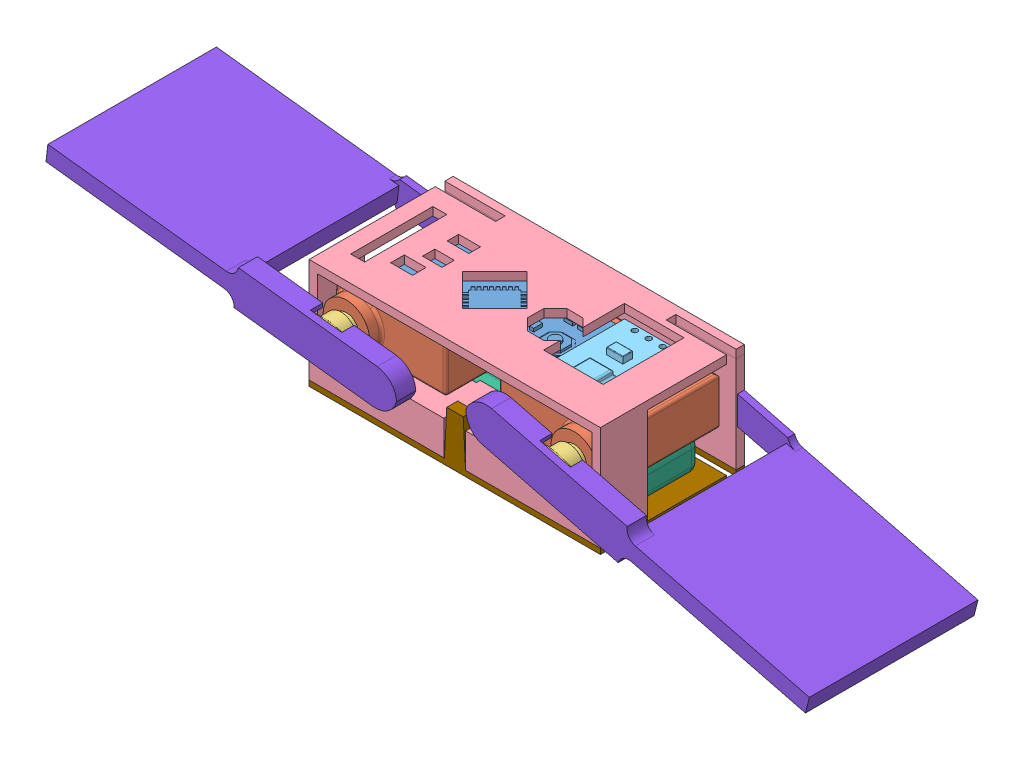
SolidWorks assembly Smarticle- Assembly, configuration Default. Lengths in mm.
Overall size (371.46 24.49 192.23).
15 component instances, 9 part files, 21 mates.
Components (placement in the parent):
- Arduino Pro Mini-1: Arduino Pro Mini [Varsayılan] at (11.3668 -0.6942 -27.9476) size (331.39 1.8 192.23)
- Servo - Assembly-1: Servo - Assembly [Default] at (118.8574 26.3366 -44.2097) x (1 0 0) z (0 -1 0) size (29.74 26.5 12.2) (flexible)
  - Servo - Body-1: Servo - Body [Default] at (-78.8577 -3.7379 27.0308) size (20.3 22.2 8.7)
  - Servo - Horn-1: Servo - Horn [Default] at (-62.9077 22.0121 31.2808) x (0.969467 0 0.245222) z (-0.245222 0 0.969467) size (27 6.5 5.75)
- Servo - Assembly-2: Servo - Assembly [Default] at (-48.4909 -36.2251 -44.2097) x (-1 0 0) z (0 1 0) size (29.69 26.5 8.83) (flexible)
  - Servo - Body-1: Servo - Body [Default] at (-78.8577 -3.7379 27.0308) size (20.3 22.2 8.7)
  - Servo - Horn-1: Servo - Horn [Default] at (-62.9077 22.0121 31.2808) x (0.993313 0 0.115453) z (-0.115453 0 0.993313) size (27 6.5 5.75)
- Case-1: Case [Default] at (8.6669 3.3558 -50.9476) x (1 0 0) z (0 -1 0) size (53.12 26.25 19.05)
- Microphone-1: Microphone [Default] at (56.3851 -0.6942 307.9213) x (0 0 1) z (-1 0 0) size (14.75 2.8 10.85)
- Battery - Assembly-1: Battery - Assembly [Default] at (3.7311 4.5627 -34.4908) x (-1 0 0) z (0 -1 0) size (45.75 12.5 7.58)
  - Battery - Body-1: Battery - Body [Default] at (-55.7734 -0.4976 13.7569) size (35.5 11.1 5.75)
  - Battery - Connector-1: Battery - Connector [Default] at (-20.2734 -1.1976 13.9319) size (10.25 12.5 7.4)
- Servo - Solar Arm-1: Servo - Solar Arm [Default] at (56.8763 -1.6973 -20.1976) x (0.969467 -0.245222 0) z (0 0 -1) size (64.2 6.75 32.5)
- Servo - Solar Arm-2: Servo - Solar Arm [Default] at (14.1286 -8.3085 -20.1976) x (-0.993313 0.115453 0) z (0 0 -1) size (64.2 6.75 32.5)
- Battery Back-1: Battery Back [Default] at (-152.2376 -16.6942 -37.1314) size (53.12 9.25 26.25)
Mates (geometry in assembly coordinates):
- Coincident5: coincident aligned: plane of Servo - Assembly-1/Servo - Body-1 through (39.9997 -0.6942 -47.9476) normal (0 1 0); plane of Servo - Assembly-2/Servo - Body-1 through (30.3669 -0.6942 -47.9476) normal (0 1 0)
- Coincident6: coincident aligned: plane of Servo - Assembly-1/Servo - Body-1 through (39.9997 -9.1942 -27.9476) normal (0 0 1); plane of Servo - Assembly-2/Servo - Body-1 through (30.3669 -0.6942 -27.9476) normal (0 0 1)
- Coincident8: coincident anti-aligned: plane of Servo - Assembly-2/Servo - Body-1 through (30.3669 -0.6942 -47.9476) normal (0 1 0); plane of Arduino Pro Mini-1 through (11.3668 -0.6942 -27.9476) normal (0 -1 0)
- Coincident15: coincident aligned: plane of Arduino Pro Mini-1 through (11.3668 0.1058 -27.9476) normal (0 0 1); plane of Servo - Assembly-2/Servo - Body-1 through (30.3669 -0.6942 -27.9476) normal (0 0 1)
- Coincident19: coincident anti-aligned: plane of Arduino Pro Mini-1 through (44.3668 0.1058 -27.9476) normal (1 0 0); plane of Microphone-1 through (44.3668 0.9058 -46.5116) normal (-1 0 0)
- Coincident20: coincident anti-aligned: plane of Servo - Assembly-1/Servo - Body-1 through (39.9997 -0.6942 -47.9476) normal (0 1 0); plane of Microphone-1 through (56.3851 -0.6942 307.9213) normal (0 -1 0)
- Parallel1: parallel anti-aligned: plane of Case-1 through (8.6669 -68.8322 -49.4476) normal (0 0 1); plane of Battery - Assembly-1/Battery - Connector-1 through (24.0046 -16.7692 -45.7932) normal (0 0 -1)
- Coincident23: coincident anti-aligned: plane of Servo - Assembly-2/Servo - Body-1 through (10.1669 -0.6942 -47.9476) normal (-1 0 0); plane of Case-1 through (10.1669 -25.1697 -24.6976) normal (1 0 0)
- Coincident24: coincident aligned: plane of Servo - Assembly-1/Servo - Body-1 through (55.2168 -9.1942 -47.9476) normal (1 0 0); plane of Microphone-1 through (55.2168 0.9058 -47.2399) normal (1 0 0)
- Coincident27: coincident anti-aligned: plane of Servo - Assembly-1/Servo - Horn-1 through (55.9497 -4.9442 -21.4476) normal (0 0 1); plane of Servo - Solar Arm-1 through (56.8763 -1.6973 -21.4476) normal (0 0 -1)
- Distance1: distance = 1.5 mm anti-aligned: plane of Servo - Assembly-1/Servo - Body-1 through (39.9997 -9.1942 -47.9476) normal (0 0 -1); plane of Case-1 through (8.6669 -68.8322 -49.4476) normal (0 0 1)
- Coincident29: coincident anti-aligned: plane of Servo - Assembly-2/Servo - Horn-1 through (14.4169 -4.9442 -21.4476) normal (0 0 1); plane of Servo - Solar Arm-2 through (14.1286 -8.3085 -21.4476) normal (0 0 -1)
- Width3: width aligned: plane of Servo - Solar Arm-2 through (14.225 -2.0906 -23.6976) normal (-0.015496 -0.99988 0); plane of Servo - Solar Arm-2 through (14.2352 -7.8225 -23.6976) normal (0.214253 0.976778 0); plane of Servo - Assembly-2/Servo - Horn-1 through (13.7983 -7.7365 -21.4476) normal (-0.216275 -0.976333 0); plane of Servo - Assembly-2/Servo - Horn-1 through (14.4553 -2.0845 -21.4476) normal (0.013425 0.99991 0)
- Width2: width anti-aligned: plane of Servo - Assembly-1/Servo - Horn-1 through (55.5351 -7.774 -21.4476) normal (-0.144951 -0.989439 0); plane of Servo - Assembly-1/Servo - Horn-1 through (56.9304 -2.2577 -21.4476) normal (0.34293 0.939361 0); plane of Servo - Solar Arm-1 through (55.9622 -7.8484 -23.6976) normal (0.146999 0.989137 0); plane of Servo - Solar Arm-1 through (56.7067 -2.165 -23.6976) normal (-0.340985 -0.940069 0)
- Coincident30: coincident anti-aligned: plane of Case-1 through (59.5046 -15.6942 -33.9932) normal (0 -1 0); plane of Battery Back-1 through (-152.2376 -15.6942 -37.1314) normal (0 1 0)
- Coincident31: coincident aligned: plane of Case-1 through (61.7837 1.8558 -50.9476) normal (1 0 0); plane of Battery Back-1 through (61.7837 -15.6942 -24.6976) normal (1 0 0)
- Coincident32: coincident aligned: plane of Case-1 through (8.6669 -68.8322 -50.9476) normal (0 0 -1); plane of Battery Back-1 through (8.6669 -15.6942 -50.9476) normal (0 0 -1)
- Coincident33: coincident anti-aligned: plane of Servo - Assembly-1/Servo - Body-1 through (39.9997 -9.1942 -47.9476) normal (0 -1 0); plane of Battery - Assembly-1/Battery - Body-1 through (59.5046 -9.1942 -33.9932) normal (0 1 0)
- Distance3: distance = 1.75 mm anti-aligned: plane of Arduino Pro Mini-1 through (11.3668 0.1058 -27.9476) normal (0 1 0); plane of Case-1 through (8.6669 1.8558 -50.9476) normal (0 -1 0)
- Symmetric2: symmetric aligned: cylinder of Servo - Solar Arm-2 through (2.4992 -3.559 -23.6976) axis (0 0 1) radius 1.65; cylinder of Servo - Solar Arm-2 through (26.5374 -6.353 -23.6976) axis (0 0 1) radius 1.65; plane of assembly through (14.8931 -1.731 0) normal (-0.993313 0.115453 0)
- Symmetric3: symmetric aligned: cylinder of Servo - Solar Arm-1 through (44.3181 -2.0021 -23.6976) axis (0 0 1) radius 1.65; cylinder of Servo - Solar Arm-1 through (67.7792 -7.9365 -23.6976) axis (0 0 1) radius 1.65; plane of assembly through (53.8596 -13.6235 0) normal (-0.969467 0.245222 0)
